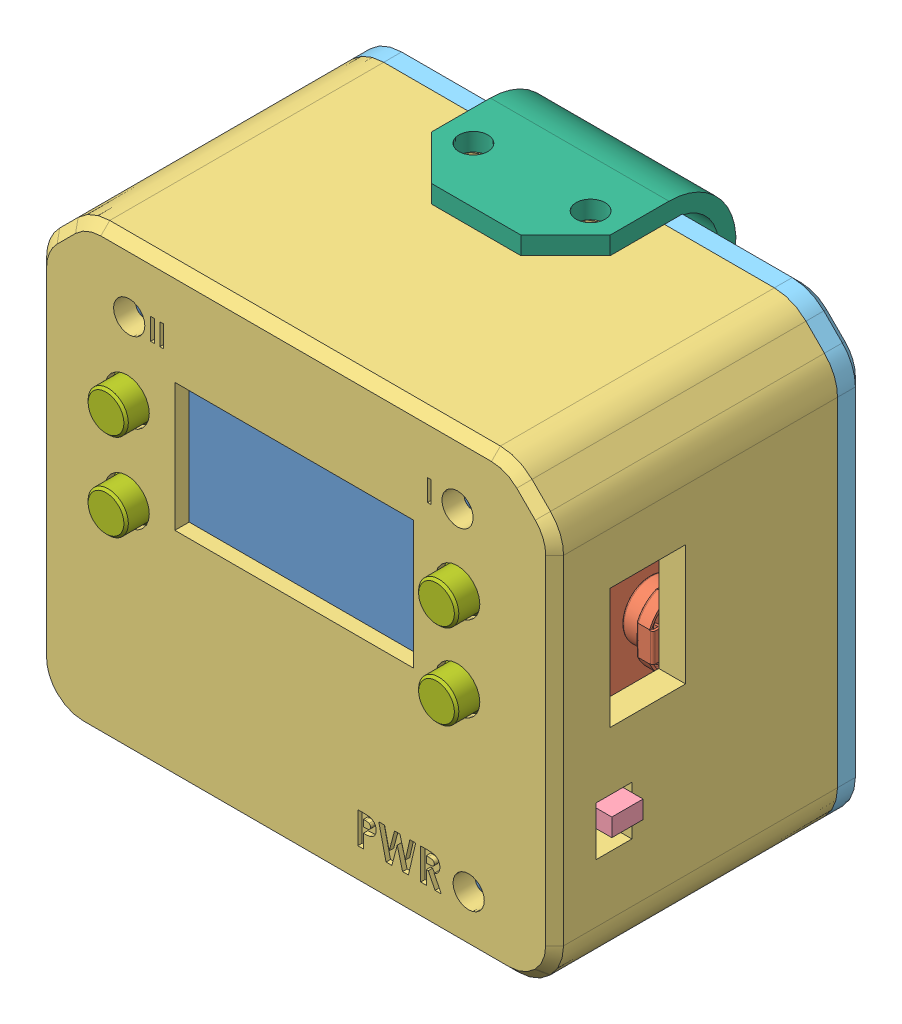
SolidWorks assembly AT005-ASSY, configuration Default. Lengths in mm.
Overall size (59.63 52 42.02).
10 component instances, 7 part files, 21 mates.
Components (placement in the parent):
- AT005-Main-PCB-1: AT005-Main-PCB [Default] at (-22.5 22.5 0) size (47.37 43.04 14.13)
- 9V-battery-1: 9V-battery [Default] at (64.7022 12.6184 -21.145) x (0 1 0) z (0 0 1) size (26.04 47.88 17.14)
- AT0005-Case-Main-1: AT0005-Case-Main [Default] at origin size (57.88 50 31.67)
- Interrupteur-1: Interrupteur [Default] at (23.634 -8.388 0.13) x (0 -1 0) z (-1 0 0) size (10.5 3.5 8.01)
- AT005-Couvercle-1: AT005-Couvercle [Default] at origin size (57.88 50 5)
- AT005-Clip-1: AT005-Clip [Default] at origin size (20.1 44.76 19.08)
- AT005-Bouton-1: AT005-Bouton [Default] at (18.5 10.5 6.38) x (0.807371 0.590044 0) z (0.590044 -0.807371 0) size (6.65 4.25 6.65)
- AT005-Bouton-2: AT005-Bouton [Default] at (18.5 1 6.38) x (0.807371 0.590044 0) z (0.590044 -0.807371 0) size (6.65 4.25 6.65)
- AT005-Bouton-3: AT005-Bouton [Default] at (-18.5 10.5 6.38) x (0.604104 0.796906 0) z (0.796906 -0.604104 0) size (6.65 4.25 6.65)
- AT005-Bouton-4: AT005-Bouton [Default] at (-18.5 0.75 6.38) x (0.943444 0.331533 0) z (0.331533 -0.943444 0) size (6.65 4.25 6.65)
Mates (geometry in assembly coordinates):
- Distance2: distance = 4 mm anti-aligned: plane of 9V-battery-1 through (-3.758 -7.4825 -4) normal (0 0 1); plane of AT005-Main-PCB-1 through (0.9442 0.0138 0) normal (0 0 -1)
- Distance3: distance = 0 mm aligned: plane of 9V-battery-1 through (-3.758 -20.5 -12.395) normal (0 -1 0); plane of AT005-Main-PCB-1 through (20.0858 -20.5 0) normal (0 -1 0)
- Distance4: distance = 2 mm aligned: plane of 9V-battery-1 through (-24.5 -7.4825 -12.395) normal (-1 0 0); plane of AT005-Main-PCB-1 through (-22.5 -18.0858 0) normal (-1 0 0)
- Coincident8: coordinate: point of assembly; point of AT0005-Case-Main-1; point of assembly
- Coincident9: coincident: moEndPointRef_w of AT005-Main-PCB-1
- Parallel1: parallel aligned: plane of AT005-Main-PCB-1 through (-22.5 22.5 0) normal (1 0 0)
- Coincident11: coincident: unknown of AT005-Main-PCB-1
- Coincident12: coincident anti-aligned: plane of AT005-Main-PCB-1 through (0.9442 0.0138 0) normal (0 0 -1)
- Coincident14: coincident anti-aligned: plane of AT0005-Case-Main-1 through (29.379 -6.888 3.63) normal (0 0 -1); plane of Interrupteur-1 through (25.1197 -6.538 3.63) normal (0 0 1)
- Coincident15: coincident anti-aligned: plane of AT0005-Case-Main-1 through (26.379 2.4616 -12.5725) normal (-1 0 0); plane of Interrupteur-1 through (26.379 -13.638 3.63) normal (1 0 0)
- Coincident16: coincident: unknown of AT005-Main-PCB-1; plane of Interrupteur-1 through (23.634 -8.388 0.13) normal (0 -1 0)
- Coincident19: coordinate: unknown of AT005-Couvercle-1
- Coincident21: coordinate: point of assembly; point of AT005-Clip-1; point of assembly
- Concentric1: concentric aligned: cylinder of AT0005-Case-Main-1 through (18.5 10.5 8.28) axis (0 0 -1) radius 2.5; cylinder of AT005-Bouton-1 through (18.5 10.5 -271.4181) axis (0 0 -1) radius 2.25
- Coincident22: coincident anti-aligned: plane of AT005-Main-PCB-1 through (17.3542 9.3542 6.63) normal (0 0 1); plane of AT005-Bouton-1 through (18.5 10.5 6.63) normal (0 0 -1)
- Concentric2: concentric aligned: cylinder of AT0005-Case-Main-1 through (18.5 1 8.28) axis (0 0 -1) radius 2.5; cylinder of AT005-Bouton-2 through (18.5 1 -271.4181) axis (0 0 -1) radius 2.25
- Concentric3: concentric aligned: cylinder of AT0005-Case-Main-1 through (-18.5 0.75 8.28) axis (0 0 -1) radius 2.5; cylinder of AT005-Bouton-4 through (-18.5 0.75 -271.4181) axis (0 0 -1) radius 2.25
- Concentric4: concentric aligned: cylinder of AT0005-Case-Main-1 through (-18.5 10.5 8.28) axis (0 0 -1) radius 2.5; cylinder of AT005-Bouton-3 through (-18.5 10.5 -271.4181) axis (0 0 -1) radius 2.25
- Coincident24: coincident anti-aligned: plane of AT005-Main-PCB-1 through (-17.3542 1.8958 6.63) normal (0 0 1); plane of AT005-Bouton-4 through (-18.5 0.75 6.63) normal (0 0 -1)
- Coincident25: coincident anti-aligned: plane of AT005-Main-PCB-1 through (-17.3542 11.6458 6.63) normal (0 0 1); plane of AT005-Bouton-3 through (-18.5 10.5 6.63) normal (0 0 -1)
- Coincident26: coincident anti-aligned: plane of AT005-Main-PCB-1 through (17.3542 -0.1458 6.63) normal (0 0 1); plane of AT005-Bouton-2 through (18.5 1 6.63) normal (0 0 -1)
